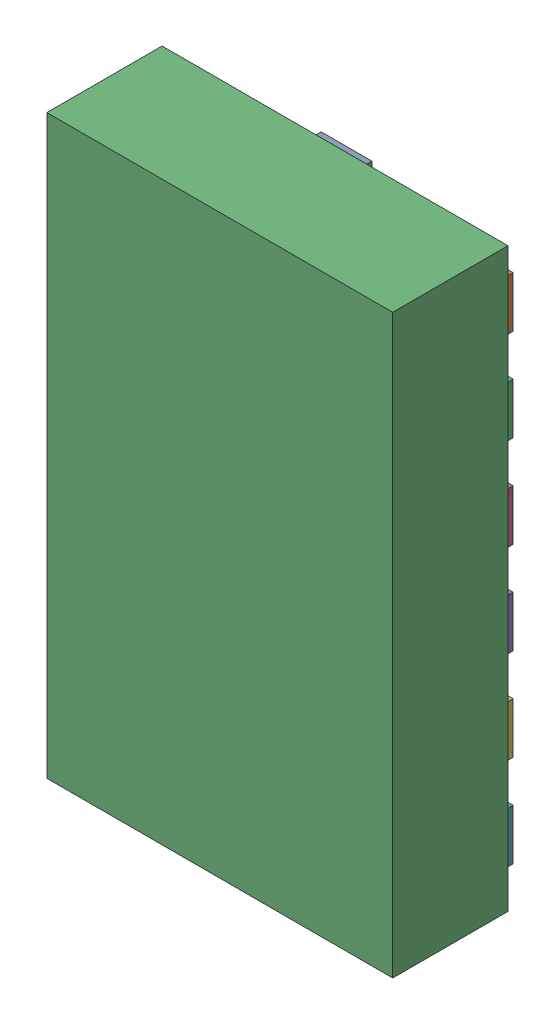
SolidWorks assembly 6074687440, configuration Predeterminado. Lengths in mm.
Overall size (3 5 1.1).
16 component instances, 15 part files, 0 mates.
Components (placement in the parent):
- 6074687440-subassembly-1-1: 6074687440-subassembly-1 [Predeterminado] at origin size (2.89 4.89 0.1)
  - Pins-1: Pins [Predeterminado] at origin size (0.44 0.86 0.1)
  - Pins-1-1: Pins-1 [Predeterminado] at origin size (0.87 0.44 0.1)
  - Pins-2-1: Pins-2 [Predeterminado] at origin size (0.87 0.44 0.1)
  - Pins-3-1: Pins-3 [Predeterminado] at origin size (0.87 0.44 0.1)
  - Pins-4-1: Pins-4 [Predeterminado] at origin size (0.87 0.44 0.1)
  - Pins-5-1: Pins-5 [Predeterminado] at origin size (0.87 0.44 0.1)
  - Pins-6-1: Pins-6 [Predeterminado] at origin size (0.87 0.44 0.1)
  - Pins-7-1: Pins-7 [Predeterminado] at origin size (0.44 0.86 0.1)
  - Pins-8-1: Pins-8 [Predeterminado] at origin size (0.87 0.44 0.1)
  - Pins-9-1: Pins-9 [Predeterminado] at origin size (0.87 0.44 0.1)
  - Pins-10-1: Pins-10 [Predeterminado] at origin size (0.87 0.44 0.1)
  - Pins-11-1: Pins-11 [Predeterminado] at origin size (0.87 0.44 0.1)
  - Pins-12-1: Pins-12 [Predeterminado] at origin size (0.87 0.44 0.1)
  - Pins-13-1: Pins-13 [Predeterminado] at origin size (0.87 0.44 0.1)
- Body-1: Body [Predeterminado] at (0 0 0.1) size (3 5 1)
